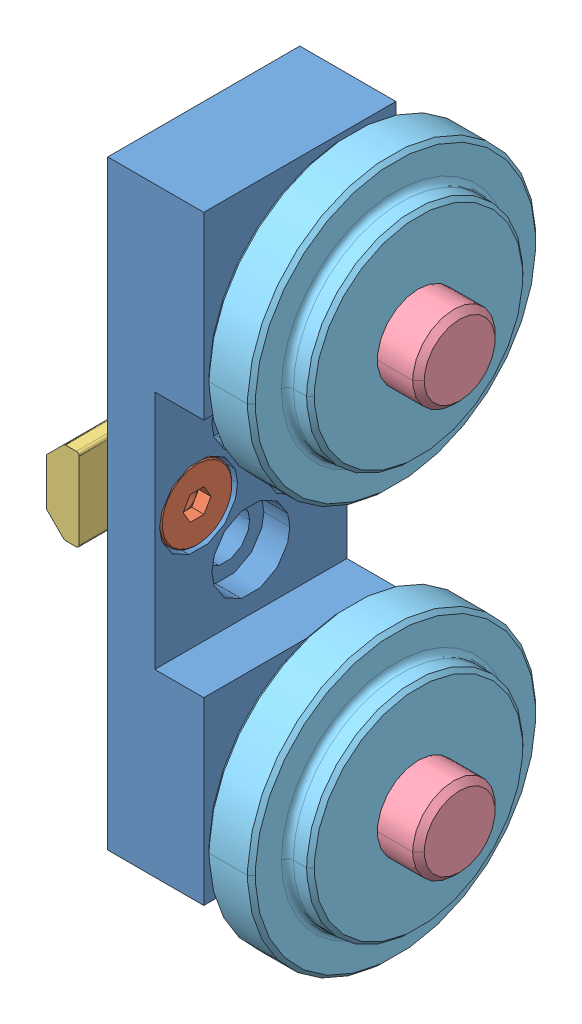
SolidWorks assembly 2751_1, configuration Default. Lengths in mm.
Overall size (40.56 92.08 38.1).
11 component instances, 6 part files, 0 mates.
Components (placement in the parent):
- _2750_1_b_2-1: _2750_1_b_2 [Default] at (6.223 0 0) x (0 0 -1) z (1 0 0) size (25.4 79.38 12.7)
- _2750_0_250_4-1: _2750_0_250_4 [Default] at (2.794 0 6.9088) x (-1 0 0) z (0 -1 0) size (12.75 9.53 9.53)
- _3204_6-1: _3204_6 [Default] at (-6.5532 0 6.9088) x (0 1 0) z (0 0 -1) size (10.95 4.34 12.45)
- _2750_0_250_4-2: _2750_0_250_4 [Default] at (2.794 0 -6.9088) x (-1 0 0) z (0 1 0) size (12.75 9.53 9.53)
- _3204_6-2: _3204_6 [Default] at (-6.5532 0 -6.9088) x (0 -1 0) z (0 0 1) size (10.95 4.34 12.45)
- _2281_b_10-1: _2281_b_10 [Default] at (28.3972 26.9875 0) x (-1 0 0) z (0 0 1) size (29.26 10.9 10.9)
- _2281_w_12-1: _2281_w_12 [Default] at (22.3012 26.9875 0) size (12.19 38.1 38.1)
- _2281_p2_14-1: _2281_p2_14 [Default] at (14.1986 26.9875 0) size (3 15.8 15.8)
- _2281_b_10-2: _2281_b_10 [Default] at (28.3972 -26.9875 0) x (-1 0 0) z (0 0 1) size (29.26 10.9 10.9)
- _2281_w_12-2: _2281_w_12 [Default] at (22.3012 -26.9875 0) size (12.19 38.1 38.1)
- _2281_p2_14-2: _2281_p2_14 [Default] at (14.1986 -26.9875 0) size (3 15.8 15.8)
